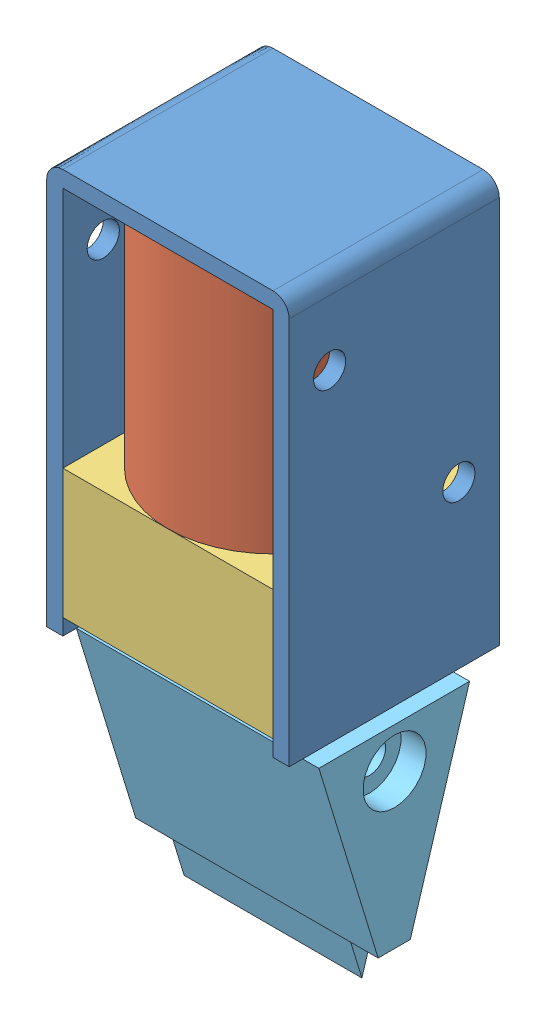
SolidWorks assembly Solenoid, configuration Default. Lengths in mm.
Overall size (15 40.57 13).
5 component instances, 5 part files, 10 mates.
Components (placement in the parent):
- External part-1: External part [Default] at (4.8787 9.4049 13.8573) x (0 -1 0) z (0 0 1) size (25 15 13)
- Coil-2: Coil [Default] at (-2.6213 18.4049 20.3573) size (13 15 13)
- Front-1: Front [Default] at (3.8787 18.4049 13.8573) x (0 0 1) z (0 -1 0) size (13 13 8)
- Plunger Solenoid-1: Plunger Solenoid [Default] at (-2.6213 28.4049 20.3573) x (0 -1 0) z (0 0 1) size (25 6 6)
- Solenoid Insert Verowhite-1: Solenoid Insert Verowhite [Default] at (-7.6213 12.9703 20.3372) x (0 0 -1) z (0 -1 0) size (9.32 15 14.57)
Mates (geometry in assembly coordinates):
- Coincident4: coincident anti-aligned: plane of External part-1 through (4.8787 33.4049 26.8573) normal (0 -1 0); plane of Coil-2 through (-2.6213 33.4049 20.3573) normal (0 1 0)
- Coincident9: coincident anti-aligned: plane of Coil-2 through (-2.6213 18.4049 20.3573) normal (0 -1 0); plane of Front-1 through (3.8787 18.4049 13.8573) normal (0 1 0)
- Coincident11: coincident anti-aligned: plane of External part-1 through (3.8787 9.4049 26.8573) normal (-1 0 0); plane of Front-1 through (3.8787 10.4049 13.8573) normal (1 0 0)
- Distance2: distance = 0 mm aligned: plane of Front-1 through (3.8787 10.4049 13.8573) normal (0 0 -1); plane of External part-1 through (4.8787 9.4049 13.8573) normal (0 0 -1)
- Concentric1: concentric anti-aligned: cylinder of Front-1 through (-2.6213 18.4049 20.3573) axis (0 -1 0) radius 3; cylinder of Plunger Solenoid-1 through (-2.6213 3.4049 20.3573) axis (0 1 0) radius 3
- Concentric2: concentric aligned: cylinder of Coil-2 through (-2.6213 28.4049 20.3573) axis (0 -1 0) radius 3; cylinder of Front-1 through (-2.6213 18.4049 20.3573) axis (0 -1 0) radius 3
- LimitDistance1: limit distance = 0 mm anti-aligned: plane of Coil-2 through (-2.6213 28.4049 20.3573) normal (0 -1 0); plane of Plunger Solenoid-1 through (-2.6213 28.4049 20.3573) normal (0 1 0)
- Concentric3: concentric aligned: cylinder of Plunger Solenoid-1 through (-2.6213 3.4049 20.3573) axis (0 1 0) radius 3; cylinder of Solenoid Insert Verowhite-1 through (-2.6213 3.4049 20.3573) axis (0 1 0) radius 3.05
- Coincident12: coincident anti-aligned: plane of Plunger Solenoid-1 through (-2.6213 3.4049 20.3573) normal (0 -1 0); plane of Solenoid Insert Verowhite-1 through (-2.6213 3.4049 20.3573) normal (0 1 0)
- Parallel2: parallel aligned: plane of External part-1 through (4.8787 9.4049 26.8573) normal (1 0 0); plane of Solenoid Insert Verowhite-1 through (4.8787 12.9703 20.3372) normal (1 0 0)
